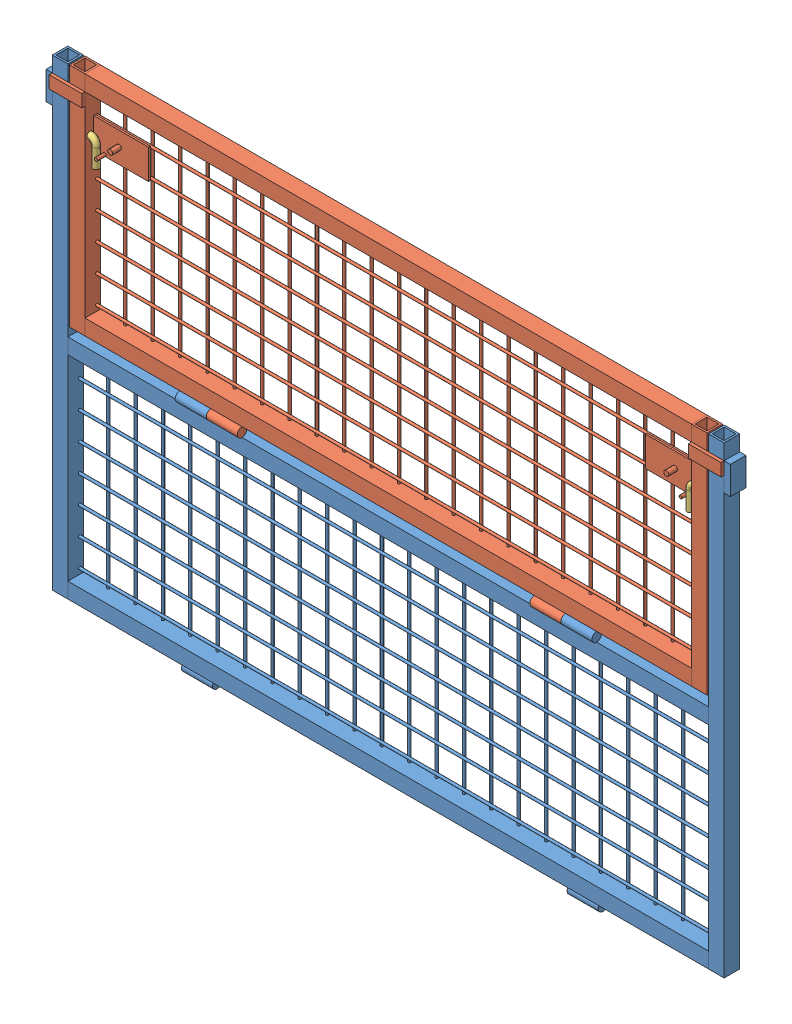
SolidWorks assembly Assieme porta anteriore, configuration Default. Lengths in mm.
Overall size (1100 760 32.5).
4 component instances, 3 part files, 4 mates.
Components (placement in the parent):
- Parte anteriore-1: Parte anteriore [Default] at (-25 -380 -10) size (1100 760 32.5)
- Porta parte anteriore-3: Porta parte anteriore [Default] at (-25 0 -10) size (1080 380 32.5)
- Fermo porta parte anteriore-1: Fermo porta parte anteriore [Default] at (-561.5 276 -5.5) size (64 45 10)
- Fermo porta parte anteriore-2: Fermo porta parte anteriore [Default] at (511.5 276 -5.5) x (-1 0 0) z (0 0 -1) size (64 45 10)
Mates (geometry in assembly coordinates):
- Cardine2: hinge = 0 rad anti-aligned: cylinder of Parte anteriore-1 through (-310 -7.5 2.5) axis (-1 0 0) radius 7.5; cylinder of Parte anteriore-1 through (-260 -7.5 2.5) axis (-1 0 0) radius 7.5; plane of Porta parte anteriore-3 through (-310 -7.5 2.5) normal (1 0 0); plane of Parte anteriore-1 through (-310 -7.5 2.5) normal (-1 0 0); plane of Porta parte anteriore-3 through (-537.5 365 -22.5) normal (0 0 -1); plane of Porta parte anteriore-3 through (-565 365 -22.5) normal (0 0 -1)
- Concentrico1: concentric anti-aligned: cylinder of Porta parte anteriore-3 through (515 276 -5.5) axis (-1 0 0) radius 5; cylinder of Fermo porta parte anteriore-1 through (-561.5 276 -5.5) axis (1 0 0) radius 5
- Parallelo1: parallel anti-aligned: plane of Fermo porta parte anteriore-1 through (-502.5 236 -5.5) normal (0 -1 0); plane of assembly through (0 0 0) normal (0 1 0)
- DistanzaLimite2: limit distance = 24 mm aligned: plane of Fermo porta parte anteriore-1 through (-561.5 276 -5.5) normal (-1 0 0); plane of Porta parte anteriore-3 through (-537.5 365 2.5) normal (-1 0 0)
